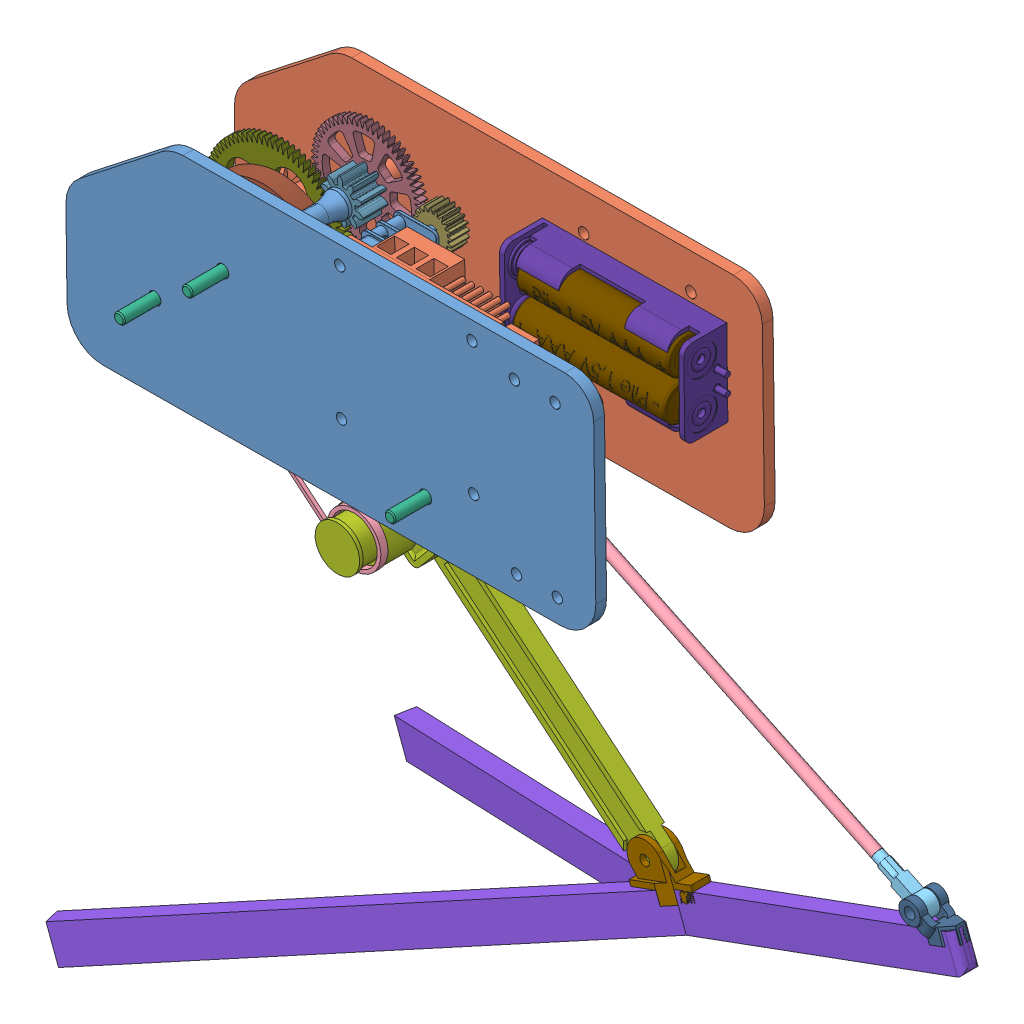
SolidWorks assembly Jumping_Robot_Tors_Spring, configuration Default. Lengths in mm.
Overall size (230.89 189.8 104.17).
33 component instances, 24 part files, 59 mates.
Components (placement in the parent):
- N20 Mini Micro Metall Gear Motor DC 3-6-12V v1.step-1: N20 Mini Micro Metall Gear Motor DC 3-6-12V v1.step [Default] at (-131.4986 -3.4428 -84.1969) x (0.001799 0.004269 -0.999989) z (-0.008933 0.999951 0.004253) size (39.8 12.15 18.58)
- L298N_Stepper_motor_driver-1: L298N_Stepper_motor_driver [Default] at (-100.2487 -4.2559 -63.6439) x (0.999958 0.008925 0.001837) z (-0.008933 0.999951 0.004253) size (43 27 43)
- PCB, Raspberry Pi Pico-R3-1: PCB, Raspberry Pi Pico-R3 [Default] at (-64.1497 -12.48 -64.1141) x (0.999958 0.008925 0.001837) z (-0.008933 0.999951 0.004253) size (21 1 51)
- Assieme3-1: Assieme3 [Default] at (-110.8693 86.7513 -90.6759) x (0.934104 -0.357002 0.000157) z (-0.356998 -0.934094 -0.00463) size (133.62 3.3 18.44)
  - Assieme5^Assieme3-1: Assieme5^Assieme3 [Default] at origin size (133.62 3.3 18.44) (virtual)
    - Copia di Assieme4^Assieme5_Assieme3-1: Copia di Assieme4^Assieme5_Assieme3 [Default] at (127.8021 8.7602 8.6279) x (0.996917 0 0.078459) z (-0.078459 0 0.996917) size (133.4 3.3 8) (virtual)
      - link_c-1: link_c [Default] at (-50.5388 -2.2091 100) size (100 3 3)
      - assembly - EYE END-1: assembly - EYE END [Default] at (104.2788 -2.2091 100) size (17.2 3.3 6)
      - assembly - EYE START_5mmdiam-1: assembly - EYE START_5mmdiam [Default] at (-99.7965 -2.2091 100) x (-1 0 0) z (0 0 -1) size (18.2 3.3 8)
- Link_a-1: Link_a [Default] at (-145.9382 -40.9033 -76.8828) x (0.642599 0.76619 0.004427) z (-0.001799 -0.004269 0.999989) size (40.84 135.59 44)
- Link_ED_finished-1: Link_ED_finished [Default] at (-15.1549 -202.8559 -80.9468) x (0.938405 0.345524 0.003164) z (-0.345534 0.9384 0.003385) size (221.73 103.39 23.94)
  - link_de-1: link_de [Default] at (0.0495 4.3921 85.8042) size (219.62 103.39 10)
  - assembly - FORK_cut-1: assembly - FORK_cut [Default] at (-4.351 4.3921 96.9859) x (0.381801 0 -0.924245) z (0.924245 0 0.381801) size (18.09 8 17.62)
  - assembly - FORK_cut_front-1: assembly - FORK_cut_front [Default] at (64.1541 4.1955 110.228) x (0.642788 0 -0.766044) z (0.766044 0 0.642788) size (14.74 8.07 8.58)
- CAM-1: CAM [Default] at (-273.0924 -111.425 -62.7096) x (0.097742 -0.993099 0.064811) z (-0.117114 -0.076148 -0.990195) size (59.38 38.88 5.5)
- gear_1_print-1: gear_1_print [Default] at (-131.6853 -3.3685 -103.1971) x (-0.008933 0.999951 0.004253) z (-0.001799 -0.004269 0.999989) size (10.98 10.98 5)
- gear_2_25teeths-1: gear_2_25teeths [Default] at (-151.6868 -3.5525 -101.9539) x (-0.949171 0.314761 -0.000364) z (-0.001799 -0.004269 0.999989) size (30.99 30.99 2)
- gear_3_11teeths-1: gear_3_11teeths [Default] at (-151.6904 -3.561 -99.9539) x (-0.932399 0.361432 -0.000135) z (-0.001799 -0.004269 0.999989) size (11.91 11.92 7)
- cam_shaft_print-1: cam_shaft_print [Default] at (-170.7634 -19.7492 -95.9573) x (-0.149537 0.988748 0.003952) z (0.988754 0.149528 0.002417) size (8 14.1 8)
- gear_4_45teeths_cut-1: gear_4_45teeths_cut [Default] at (-170.7634 -19.7492 -95.9573) x (0.988754 0.149528 0.002417) z (-0.001799 -0.004269 0.999989) size (40.99 40.99 2)
- Coupleur + 2xAAA-1: Coupleur + 2xAAA [Default] at (-107.9244 6.9357 -106.6104) x (-0.008933 0.999951 0.004253) z (0.999958 0.008925 0.001837) size (25.73 14.75 54.6)
  - Coupleur 2xAAA-1: Coupleur 2xAAA [Défaut] at origin size (24 12 54.6)
  - Pile 1,5V LR3 AAA-1: Pile 1,5V LR3 AAA [Défaut] at (-18 7.6699 44.934) x (0 0 -1) z (0.453786 0.891111 0) size (44.1 10 10.1)
  - Pile 1,5V LR3 AAA-2: Pile 1,5V LR3 AAA [Défaut] at (-6 7.6699 3.866) x (0 0 1) z (-0.602723 0.79795 0) size (44.1 10 10.1)
- Body-1: Body [Default] at (-109.8243 -25.0566 -219.1463) x (0.999958 0.008925 0.001837) z (-0.001799 -0.004269 0.999989) size (148 62 50)
  - Plate_dx_print-1: Plate_dx_print [Default] at (53.8252 -17.6378 156.3946) size (148 62 32.62)
  - Plate_sx_print-1: Plate_sx_print [Default] at (-6.7243 7.6417 112.3946) x (-1 0 0) z (0 0 -1) size (148 62 23.6)
- spring1-1: spring1 [Default] at (-145.618 -34.4959 -102.8551) x (-0.766201 0.6426 0.001365) z (-0.001799 -0.004269 0.999989) size (63.62 46.07 6.5)
- spring2-1: spring2 [Default] at (-145.681 -34.6454 -67.8555) x (0.960224 0.279217 0.00292) z (0.001799 0.004269 -0.999989) size (63.62 46.07 6.5)
- cam_cylinder-1: cam_cylinder [Default] at (-161.6705 -27.5975 -96.5235) x (-0.800773 -0.582496 0.139505) z (0.117114 0.076148 0.990195) size (3 3 14.05)
- Hexagon head screw ISO 4017- M3 × 60-1: Hexagon head screw ISO 4017- M3 × 60 [Default] at (-170.7348 -19.6814 -111.8371) x (0.999998 -0.000004 0.001799) z (-0.001799 -0.004269 0.999989) size (6.35 5.5 62)
- Hexagon head screw ISO 4017- M3 × 60-2: Hexagon head screw ISO 4017- M3 × 60 [Default] at (-151.6692 -3.5107 -111.7338) x (0.999998 -0.000004 0.001799) z (-0.001799 -0.004269 0.999989) size (6.35 5.5 62)
- Hexagon head screw ISO 4017- M3 × 60-3: Hexagon head screw ISO 4017- M3 × 60 [Default] at (-95.0204 -29.81 -111.7442) x (0.999998 -0.000004 0.001799) z (-0.001799 -0.004269 0.999989) size (6.35 5.5 62)
Mates (geometry in assembly coordinates):
- Coincidente3: coincident anti-aligned: plane of Link_a-1 through (-56.1328 -109.6584 -83.5148) normal (-0.001799 -0.004269 0.999989); plane of Link_ED_finished-1/assembly - FORK_cut-1 through (-338877.0294 367578.3592 876.5872) normal (0.001799 0.004269 -0.999989)
- Concentrico2: concentric aligned: circle of Link_a-1; circle of Link_ED_finished-1/assembly - FORK_cut-1
- Coincidente20: coincident aligned: plane of N20 Mini Micro Metall Gear Motor DC 3-6-12V v1.step-1 through (-129.5727 -5.2199 -103.2012) normal (0.001799 0.004269 -0.999989); plane of gear_1_11teeths-1 through (-131.6853 -3.3685 -103.1971) normal (0.001799 0.004269 -0.999989)
- Coincidente21: coincident anti-aligned: plane of N20 Mini Micro Metall Gear Motor DC 3-6-12V v1.step-1 through (-130.461 -5.3868 -95.2035) normal (0.999958 0.008925 0.001837); plane of gear_1_11teeths-1 through (-130.4547 -4.4476 -103.1995) normal (-0.999958 -0.008925 -0.001837)
- Parallelo6: parallel aligned: plane of L298N_Stepper_motor_driver-1 through (-100.2487 -4.2559 -63.6439) normal (-0.001799 -0.004269 0.999989); plane of Link_a-1 through (-145.9373 -40.9012 -77.3827) normal (-0.001799 -0.004269 0.999989)
- Coincidente26: coincident aligned: plane of L298N_Stepper_motor_driver-1 through (-100.2487 -4.2559 -63.6439) normal (-0.001799 -0.004269 0.999989); plane of PCB, Raspberry Pi Pico-R3-1 through (-64.1506 -12.4821 -63.6141) normal (-0.001799 -0.004269 0.999989)
- Coincidente29: coincident aligned: circle of N20 Mini Micro Metall Gear Motor DC 3-6-12V v1.step-1; plane of L298N_Stepper_motor_driver-1 through (-100.2487 -4.2559 -63.6439) normal (-0.001799 -0.004269 0.999989)
- Coincidente30: coincident anti-aligned: line of N20 Mini Micro Metall Gear Motor DC 3-6-12V v1.step-1 through (-130.4879 -2.2668 -95.6902) axis (0.001799 0.004269 -0.999989); line of gear_1_11teeths-1 through (-130.4744 -2.2348 -103.1901) axis (-0.001799 -0.004269 0.999989)
- Parallelo11: parallel aligned: plane of PCB, Raspberry Pi Pico-R3-1 through (-64.1488 -12.4779 -64.6141) normal (0.001799 0.004269 -0.999989); plane of Coupleur + 2xAAA-1/Coupleur 2xAAA-1 through (-58.9121 -16.6276 -106.6228) normal (0.001799 0.004269 -0.999989)
- Parallelo12: parallel aligned: plane of Coupleur + 2xAAA-1/Coupleur 2xAAA-1 through (-109.1494 -14.6163 -97.2037) normal (-0.999958 -0.008925 -0.001837); plane of L298N_Stepper_motor_driver-1 through (-121.9363 17.0597 -65.592) normal (-0.999958 -0.008925 -0.001837)
- Parallelo16: parallel aligned: plane of Link_a-1 through (-56.1328 -109.6584 -83.5148) normal (-0.001799 -0.004269 0.999989); plane of Body-1/Plate_dx_print-1 through (-57.4582 -32.315 -59.6867) normal (-0.001799 -0.004269 0.999989)
- Concentrico24: concentric: cylinder of Link_a-1; cylinder of Body-1/Plate_sx_print-1 through (-145.6422 -34.5531 -89.4552) axis (0.001799 0.004269 -0.999989) radius 2.35
- Concentrico26: concentric anti-aligned: circle of gear_2_25teeths-1; cylinder of Body-1/Plate_sx_print-1 through (-151.704 -3.5934 -92.354) axis (0.001799 0.004269 -0.999989) radius 2.2
- Coincidente36: coincident anti-aligned: plane of gear_2_25teeths-1 through (-151.6868 -3.5525 -101.9539) normal (0.001799 0.004269 -0.999989); plane of Body-1/Plate_sx_print-1 through (-151.6868 -3.5525 -101.9539) normal (-0.001799 -0.004269 0.999989)
- Concentrico27: concentric anti-aligned: circle of gear_3_11teeths-1; cylinder of Body-1/Plate_sx_print-1 through (-151.704 -3.5934 -92.354) axis (0.001799 0.004269 -0.999989) radius 2.2
- Coincidente37: coincident anti-aligned: plane of gear_2_25teeths-1 through (-151.6904 -3.561 -99.9539) normal (-0.001799 -0.004269 0.999989); plane of gear_3_11teeths-1 through (-151.6904 -3.561 -99.9539) normal (0.001799 0.004269 -0.999989)
- Concentrico28: concentric: circle of gear_4_45teeths_cut-1; cylinder of Body-1/Plate_sx_print-1 through (-170.7772 -19.782 -88.2674) axis (0.001799 0.004269 -0.999989) radius 2.4
- Coincidente38: coincident: plane of gear_4_45teeths_cut-1 through (-170.7634 -19.7492 -95.9573) normal (0.001799 0.004269 -0.999989); plane of Body-1/Plate_sx_print-1 through (-170.7634 -19.7492 -95.9573) normal (-0.001799 -0.004269 0.999989)
- Concentrico29: concentric: cylinder of cam_shaft-1 through (-170.7888 -19.8094 -81.8575) axis (0.001799 0.004269 -0.999989) radius 4; cylinder of Body-1/Plate_sx_print-1 through (-170.7772 -19.782 -88.2674) axis (0.001799 0.004269 -0.999989) radius 2.4
- Coincidente40: coincident: plane of cam_shaft-1 through (-171.1782 -17.0386 -93.9465) normal (-0.988754 -0.149528 -0.002417); plane of gear_4_45teeths_cut-1 through (-171.5092 -17.4002 -85.9485) normal (0.988754 0.149528 0.002417)
- Coincidente41: coincident: plane of cam_shaft-1 through (-170.7634 -19.7492 -95.9573) normal (0.001799 0.004269 -0.999989); plane of gear_4_45teeths_cut-1 through (-170.7634 -19.7492 -95.9573) normal (0.001799 0.004269 -0.999989)
- Coincidente43: coincident: plane of CAM-1 through (-169.407 -16.3721 -77.738) normal (-0.988297 -0.089193 0.123748); plane of cam_shaft-1 through (-171.1899 -17.0664 -87.4465) normal (0.988754 0.149528 0.002417)
- Concentrico30: concentric: cylinder of CAM-1 through (-169.3898 -18.8648 -77.5483) axis (-0.117114 -0.076148 -0.990195) radius 4.25; cylinder of Body-1/Plate_dx_print-1 through (-170.7772 -19.782 -88.2674) axis (-0.001799 -0.004269 0.999989) radius 2.2
- Coincidente44: coincident: plane of CAM-1 through (-146.2504 -20.1307 -90.2868) normal (-0.117114 -0.076148 -0.990195); plane of cam_shaft-1 through (-170.7787 -19.7855 -87.4574) normal (-0.001799 -0.004269 0.999989)
- AccoppiamentoCamTangente5: cam tangent: cylinder of assembly; face of CAM-1; cylinder of Link_a-1 through (-171.2319 -52.4942 -84.9778) axis (-0.001799 -0.004269 0.999989) radius 2.5
- Concentrico32: concentric aligned: circle of spring2-1; circle of Body-1/Plate_dx-1
- Parallelo18: parallel anti-aligned: plane of Body-1/Plate_sx_print-1 through (-185.5788 -9.0769 -109.8186) normal (0.001799 0.004269 -0.999989); plane of spring2-1 through (-145.681 -34.6454 -67.8555) normal (-0.001799 -0.004269 0.999989)
- Parallelo19: parallel aligned: plane of Link_a-1 through (-144.7569 -41.8767 -79.8848) normal (-0.642599 -0.76619 -0.004427); plane of spring2-1 through (-151.9468 -42.4331 -68.9) normal (-0.642599 -0.76619 -0.004427)
- Concentrico37: concentric: cylinder of Body-1/Plate_sx_print-1 through (-145.6108 -34.4789 -106.8551) axis (-0.001799 -0.004269 0.999989) radius 7.5; circle of spring1-1
- Parallelo20: parallel aligned: plane of Link_a-1 through (-144.7569 -41.8767 -79.8848) normal (-0.642599 -0.76619 -0.004427); plane of spring1-1 through (-152.0503 -42.1728 -99.3994) normal (-0.642599 -0.76619 -0.004427)
- Coincidente50: coincident anti-aligned: plane of Link_a-1 through (-122.3842 -57.441 -68.9109) normal (-0.001799 -0.004269 0.999989); plane of spring2-1 through (-145.6792 -34.6411 -68.8555) normal (0.001799 0.004269 -0.999989)
- Coincidente51: coincident anti-aligned: plane of Link_a-1 through (-122.3329 -57.3194 -97.4106) normal (0.001799 0.004269 -0.999989); plane of spring1-1 through (-122.3329 -57.3194 -97.4106) normal (-0.001799 -0.004269 0.999989)
- Concentrico46: concentric aligned: circle of gear_1_11teeths-1; circle of Body-1/Plate_dx-1
- Perpendicolare1: perpendicular: plane of N20 Mini Micro Metall Gear Motor DC 3-6-12V v1.step-1 through (-137.5563 1.4386 -68.9868) normal (-0.999958 -0.008925 -0.001837); plane of Body-1/Plate_dx_print-1 through (-162.7466 18.7468 -59.6582) normal (-0.008933 0.999951 0.004253)
- Coincidente55: coincident anti-aligned: plane of L298N_Stepper_motor_driver-1 through (-100.2487 -4.2559 -63.6439) normal (-0.001799 -0.004269 0.999989); plane of Body-1/Plate_dx_print-1 through (-81.9148 14.4083 -63.5313) normal (0.001799 0.004269 -0.999989)
- Concentrico47: concentric aligned: circle of L298N_Stepper_motor_driver-1; circle of Body-1/Plate_dx-1
- Concentrico49: concentric aligned: circle of L298N_Stepper_motor_driver-1; circle of Body-1/Plate_dx-1
- Concentrico50: concentric aligned: circle of PCB, Raspberry Pi Pico-R3-1; circle of Body-1/Plate_dx-1
- Concentrico51: concentric aligned: circle of PCB, Raspberry Pi Pico-R3-1; circle of Body-1/Plate_dx-1
- Coincidente56: coincident anti-aligned: plane of PCB, Raspberry Pi Pico-R3-1 through (-64.1506 -12.4821 -63.6141) normal (-0.001799 -0.004269 0.999989); plane of Body-1/Plate_dx_print-1 through (-58.6607 11.0676 -63.5037) normal (0.001799 0.004269 -0.999989)
- Coincidente57: coincident anti-aligned: plane of Coupleur + 2xAAA-1/Coupleur 2xAAA-1 through (-58.9121 -16.6276 -106.6228) normal (0.001799 0.004269 -0.999989); plane of Body-1/Plate_sx_print-1 through (-185.5842 -9.0897 -106.8186) normal (-0.001799 -0.004269 0.999989)
- Distanza10: distance = 12.5 mm aligned: plane of Coupleur + 2xAAA-1/Coupleur 2xAAA-1 through (-59.1264 7.3712 -106.5208) normal (-0.008933 0.999951 0.004253); plane of Body-1/Plate_sx_print-1 through (-55.8329 19.9138 -109.4613) normal (-0.008933 0.999951 0.004253)
- Distanza11: distance = 10 mm aligned: plane of Coupleur + 2xAAA-1/Coupleur 2xAAA-1 through (-57.5515 -14.1558 -97.1089) normal (0.999958 0.008925 0.001837); plane of Body-1/Plate_sx_print-1 through (-47.3687 -32.0123 -109.6678) normal (0.999958 0.008925 0.001837)
- Concentrico52: concentric: circle of cam_cylinder-1; circle of CAM-1
- Coincidente59: coincident aligned: plane of CAM-1 through (-145.6063 -19.7119 -84.8407) normal (0.117114 0.076148 0.990195); plane of cam_cylinder-1 through (-160.025 -26.5276 -82.6112) normal (0.117114 0.076148 0.990195)
- Coincidente60: coincident anti-aligned: plane of Link_a-1 through (-146.0187 -43.3535 -92.8935) normal (0.001799 0.004269 -0.999989); plane of Body-1/Plate_sx_print-1 through (-145.636 -34.5386 -92.8552) normal (-0.001799 -0.004269 0.999989)
- Concentrico53: concentric aligned: circle of Assieme3-1/Assieme5^Assieme3-1/Copia di Assieme4^Assieme5_Assieme3-1/assembly - EYE START_5mmdiam-1; cylinder of Body-1/Plate_dx_print-1 through (-95.0665 -29.9193 -86.1444) axis (-0.001799 -0.004269 0.999989) radius 2.2
- Concentrico54: concentric aligned: circle of Assieme3-1/Assieme5^Assieme3-1/Copia di Assieme4^Assieme5_Assieme3-1/assembly - EYE END-1; circle of Link_ED_finished-1/assembly - FORK_cut_front-1
- Coincidente61: coincident anti-aligned: plane of Assieme3-1/Assieme5^Assieme3-1/Copia di Assieme4^Assieme5_Assieme3-1/assembly - EYE END-1 through (45180.518 -21542.1807 -93.3208) normal (-0.001799 -0.004269 0.999989); plane of Link_ED_finished-1/assembly - FORK_cut_front-1 through (-43372.9501 24750.2641 -55.022) normal (0.001799 0.004269 -0.999989)
- Concentrico55: concentric aligned: circle of Body-1/Plate_sx-1; cylinder of Hexagon head screw ISO 4017- M3 × 60-1 through (-170.8464 -19.9461 -49.8378) axis (0.001799 0.004269 -0.999989) radius 1.5
- Coincidente62: coincident anti-aligned: plane of Body-1/Plate_sx_print-1 through (-185.5788 -9.0769 -109.8186) normal (0.001799 0.004269 -0.999989); plane of Hexagon head screw ISO 4017- M3 × 60-1 through (-167.563 -19.6899 -109.8314) normal (-0.001799 -0.004269 0.999989)
- Concentrico56: concentric aligned: circle of Body-1/Plate_sx-1; cylinder of Hexagon head screw ISO 4017- M3 × 60-2 through (-151.7807 -3.7754 -49.7345) axis (0.001799 0.004269 -0.999989) radius 1.5
- Coincidente63: coincident anti-aligned: plane of Body-1/Plate_sx_print-1 through (-185.5788 -9.0769 -109.8186) normal (0.001799 0.004269 -0.999989); plane of Hexagon head screw ISO 4017- M3 × 60-2 through (-148.4973 -3.5193 -109.7281) normal (-0.001799 -0.004269 0.999989)
- Concentrico57: concentric aligned: circle of Body-1/Plate_sx-1; cylinder of Hexagon head screw ISO 4017- M3 × 60-3 through (-95.132 -30.0747 -49.7448) axis (0.001799 0.004269 -0.999989) radius 1.5
- Coincidente64: coincident anti-aligned: plane of Body-1/Plate_sx_print-1 through (-185.5788 -9.0769 -109.8186) normal (0.001799 0.004269 -0.999989); plane of Hexagon head screw ISO 4017- M3 × 60-3 through (-91.8486 -29.8186 -109.7385) normal (-0.001799 -0.004269 0.999989)
- Concentrico58: concentric aligned: circle of Assieme3-1/Assieme5^Assieme3-1/Copia di Assieme4^Assieme5_Assieme3-1/assembly - EYE END-1; circle of Link_ED_finished-1/assembly - FORK_cut_front-1
- Concentrico60: concentric anti-aligned: circle of Link_a-1; circle of spring1-1
- Coincidente65: coincident anti-aligned: plane of Link_a-1 through (-122.3329 -57.3194 -97.4106) normal (0.001799 0.004269 -0.999989); circle of spring1-1
- Coincidente66: coincident aligned: plane of Link_a-1 through (-122.3842 -57.441 -68.9109) normal (-0.001799 -0.004269 0.999989); circle of spring2-1
